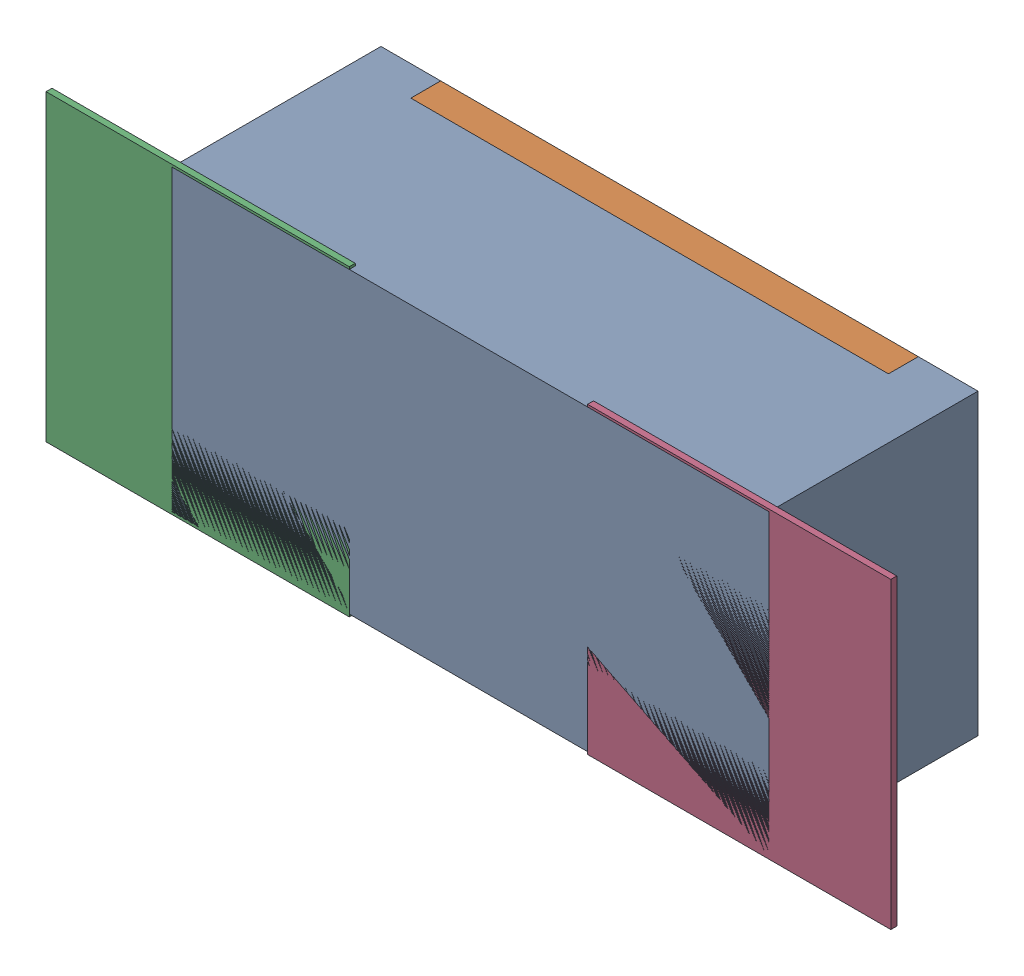
SolidWorks assembly R104, configuration Défaut. Lengths in mm.
Overall size (1.42 0.51 0.35).
5 component instances, 2 part files, 0 mates.
Components (placement in the parent):
- R0402-1: R0402 [Défaut] at (20.574 -25.4507 -2.0818) x (1 0 0) z (0 0 -1) size (1 0.5 0.35)
- 6504207776-1: 6504207776 [Défaut] at (20.1169 -25.4509 -2.0918) size (0.51 0.51 0.01)
  - Extruded-1: Extruded [Défaut] at origin size (0.51 0.51 0.01)
- 6504207776-2: 6504207776 [Défaut] at (21.024 -25.4509 -2.0918) size (0.51 0.51 0.01)
  - Extruded-1: Extruded [Défaut] at origin size (0.51 0.51 0.01)
